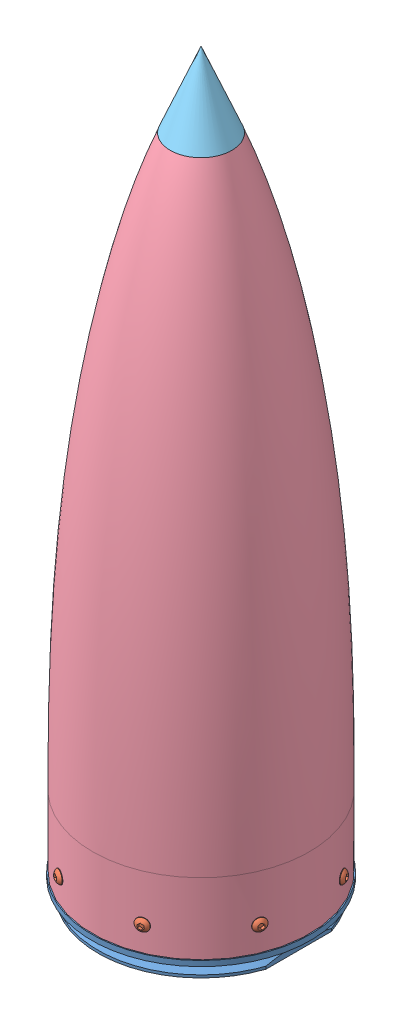
SolidWorks assembly Nosecone, configuration Standard. Lengths in mm.
Overall size (161.7 415.71 161.7).
22 component instances, 7 part files, 8 mates.
Components (placement in the parent):
- R1-2_clampband_top_coupler-1: R1-2_clampband_top_coupler [Standard] at origin size (123 32.37 123)
- Fastener_ButtonHead_M4_5-1: Fastener_ButtonHead_M4_5 [Default] at (-56.3567 25 -23.3437) x (-0.146447 0.92388 0.353553) z (-0.353553 -0.382683 0.853553) size (7 6.91 7)
- studbolt_din-3: studbolt_din [DIN 976-1 -- M3 x 10  A--  N] at (-57 8 0) x (0 1 0) z (0 0 1) size (10 3 3)
- studbolt_din-4: studbolt_din [DIN 976-1 -- M3 x 10  A--  N] at (-40.3051 8 -40.3051) x (0 1 0) z (-0.707107 0 0.707107) size (10 3 3)
- studbolt_din-5: studbolt_din [DIN 976-1 -- M3 x 10  A--  N] at (0 8 -57) x (0 1 0) z (-1 0 0) size (10 3 3)
- studbolt_din-6: studbolt_din [DIN 976-1 -- M3 x 10  A--  N] at (40.3051 8 -40.3051) x (0 1 0) z (-0.707107 0 -0.707107) size (10 3 3)
- studbolt_din-7: studbolt_din [DIN 976-1 -- M3 x 10  A--  N] at (57 8 0) x (0 1 0) z (0 0 -1) size (10 3 3)
- studbolt_din-8: studbolt_din [DIN 976-1 -- M3 x 10  A--  N] at (40.3051 8 40.3051) x (0 1 0) z (0.707107 0 -0.707107) size (10 3 3)
- studbolt_din-9: studbolt_din [DIN 976-1 -- M3 x 10  A--  N] at (0 8 57) x (0 1 0) z (1 0 0) size (10 3 3)
- studbolt_din-10: studbolt_din [DIN 976-1 -- M3 x 10  A--  N] at (-40.3051 8 40.3051) x (0 1 0) z (0.707107 0 0.707107) size (10 3 3)
- A1_Nosecone-1: A1_Nosecone [Standard] at (0 401.0875 0) x (0.92388 0 -0.382683) z (0 1 0) size (123.76 123.76 402.33)
  - Nosecone_Nosecone-1: Nosecone_Nosecone [Standard] x (0 0 -1) z (-1 0 0) size (360.09 123.76 123.76)
  - Nosecone_Alutip-1: Nosecone_Alutip [Standard] x (0 0 -1) z (1 0 0) size (72.25 34.63 34.63)
  - Nosecone_PLA_Insert-1: Nosecone_PLA_Insert [Standard] x (0 0 -1) z (1 0 0) size (20.14 48.68 48.68)
  - Nosecone_M10_Nut-1: Nosecone_M10_Nut [Standard] at (0 0 -47.9885) x (0.866025 -0.5 0) z (0 0 1) size (19.48 17 7.7)
- Fastener_ButtonHead_M4_5-9: Fastener_ButtonHead_M4_5 [Default] at (-56.3567 25 23.3437) x (0.146447 0.92388 0.353553) z (0.353553 -0.382683 0.853553) size (7 6.91 7)
- Fastener_ButtonHead_M4_5-10: Fastener_ButtonHead_M4_5 [Default] at (-23.3437 25 56.3567) x (0.353553 0.92388 0.146447) z (0.853553 -0.382683 0.353553) size (7 6.91 7)
- Fastener_ButtonHead_M4_5-11: Fastener_ButtonHead_M4_5 [Default] at (23.3437 25 56.3567) x (0.353553 0.92388 -0.146447) z (0.853553 -0.382683 -0.353553) size (7 6.91 7)
- Fastener_ButtonHead_M4_5-12: Fastener_ButtonHead_M4_5 [Default] at (56.3567 25 23.3437) x (0.146447 0.92388 -0.353553) z (0.353553 -0.382683 -0.853553) size (7 6.91 7)
- Fastener_ButtonHead_M4_5-13: Fastener_ButtonHead_M4_5 [Default] at (56.3567 25 -23.3437) x (-0.146447 0.92388 -0.353553) z (-0.353553 -0.382683 -0.853553) size (7 6.91 7)
- Fastener_ButtonHead_M4_5-14: Fastener_ButtonHead_M4_5 [Default] at (23.3437 25 -56.3567) x (-0.353553 0.92388 -0.146447) z (-0.853553 -0.382683 -0.353553) size (7 6.91 7)
- Fastener_ButtonHead_M4_5-15: Fastener_ButtonHead_M4_5 [Default] at (-23.3437 25 -56.3567) x (-0.353553 0.92388 0.146447) z (-0.853553 -0.382683 0.353553) size (7 6.91 7)
Mates (geometry in assembly coordinates):
- Konzentrisch1: concentric: cylinder of R1-2_clampband_top_coupler-1 through (0 0 0) axis (0 -1 0) radius 53
- Deckungsgleich2: coincident: plane of R1-2_clampband_top_coupler-1 through (-58 0 0) normal (0 -1 0)
- Konzentrisch7: concentric anti-aligned: cylinder of R1-2_clampband_top_coupler-1 through (-57 -0.001 0) axis (0 1 0) radius 1.25; cylinder of Fastener_ThreadedRod_M3_10-3 through (-57 4.825 0) axis (0 -1 0) radius 1.5
- Abstand2: distance = 5 mm aligned: plane of studbolt_din-3 through (-58.5 18 0) normal (0 1 0); plane of R1-2_clampband_top_coupler-1 through (-53 13 0) normal (0 1 0)
- Konzentrisch8: concentric anti-aligned: cylinder of R1-2_clampband_top_coupler-1 through (0 0 0) axis (0 -1 0) radius 60; cylinder of A1_Nosecone-1/Nosecone_Nosecone-1 through (0 401.0875 0) axis (0 1 0) radius 61
- Konzentrisch10: concentric aligned: cylinder of R1-2_clampband_top_coupler-1 through (-74.2371 25 -30.75) axis (0.92388 0 0.382683) radius 1.65; cylinder of A1_Nosecone-1/Nosecone_Nosecone-1 through (-80.8518 25 -33.4899) axis (0.92388 0 0.382683) radius 2
- Konzentrisch12: concentric anti-aligned: cylinder of R1-2_clampband_top_coupler-1 through (-74.2371 25 -30.75) axis (0.92388 0 0.382683) radius 1.65; cylinder of Fastener_ButtonHead_M4_5-1 through (-51.7373 25 -21.4303) axis (-0.92388 0 -0.382683) radius 2
- Tangential1: tangent anti-aligned: plane of Fastener_ButtonHead_M4_5-1 through (-55.8441 21.7664 -24.5811) normal (0.92388 0 0.382683); cylinder of A1_Nosecone-1/Nosecone_Nosecone-1 through (0 401.0875 0) axis (0 1 0) radius 61
